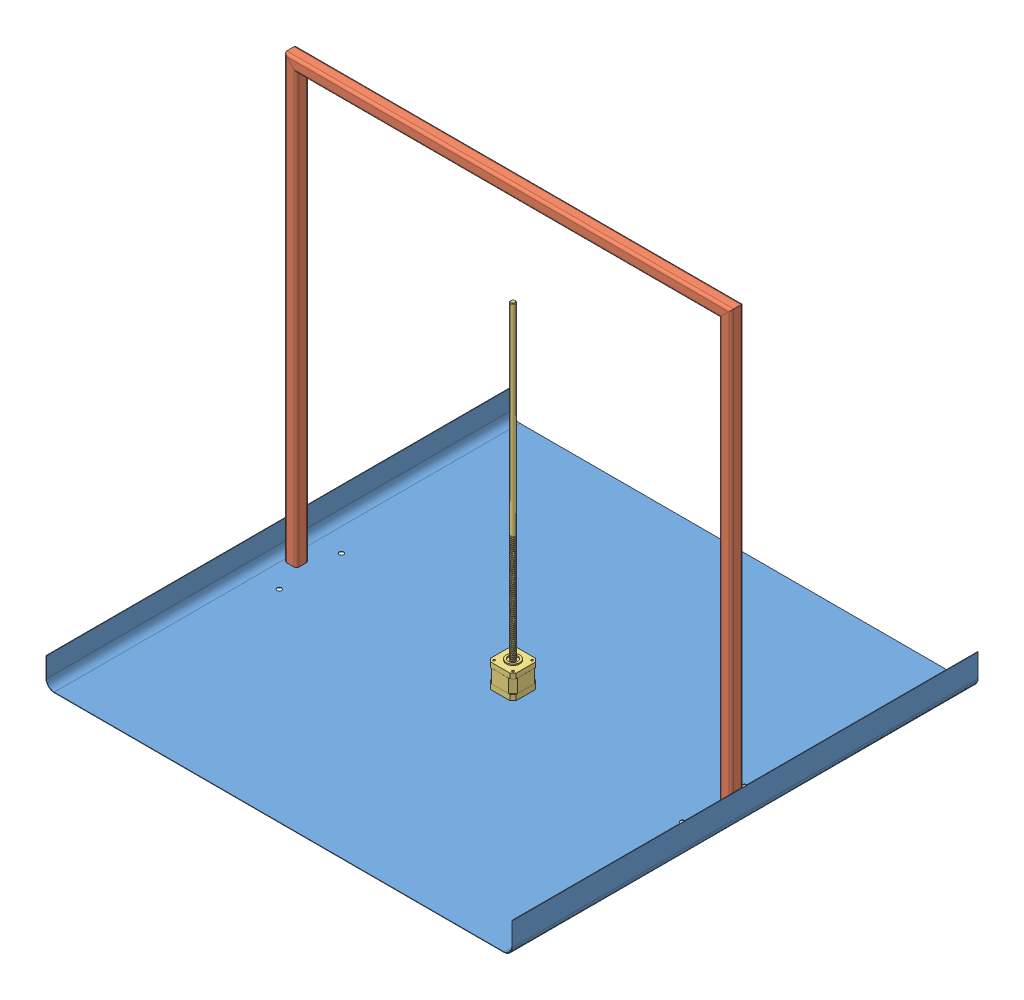
SolidWorks assembly Assem2, configuration Default. Lengths in mm.
Overall size (762.74 721.94 762).
3 component instances, 3 part files, 2 mates.
Components (placement in the parent):
- Base parking1-1: Base parking1 [Default] at (341.6569 193.3938 705.3071) size (762.74 51.54 762)
- Stand pillar-1: Stand pillar [Default<As Machined>] at (-62.6207 193.3938 1083.7527) size (731.2 721.2 20)
- Motor screw-2: Motor screw [Valor predeterminado] at (293.3866 193.3938 1085.5248) size (42.1 547 42.1)
Mates (geometry in assembly coordinates):
- Coincident2: coincident anti-aligned: plane of Base parking1-1 through (-88.885 193.3938 1467.3071) normal (0 1 0); plane of Stand pillar-1 through (642.5793 193.3938 1077.7527) normal (0 -1 0)
- Coincident3: coincident anti-aligned: plane of Base parking1-1 through (-88.885 193.3938 1467.3071) normal (0 1 0); plane of Motor screw-2 through (293.3866 193.3938 1085.5248) normal (0 -1 0)
